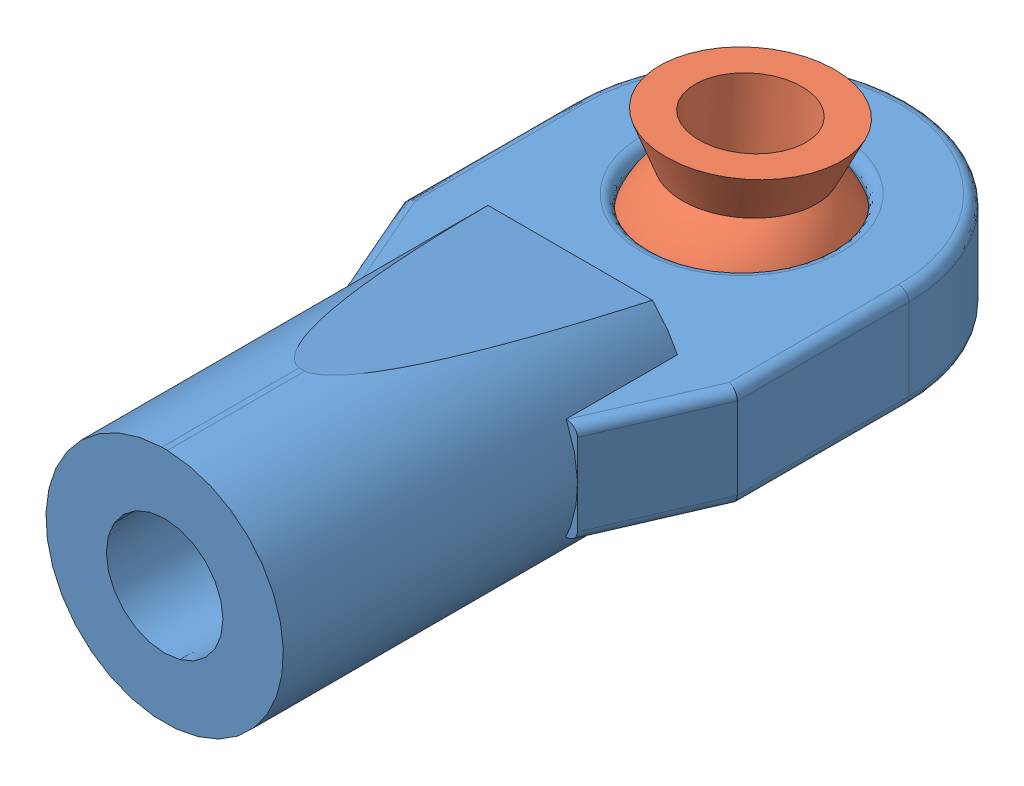
SolidWorks assembly Traxxas_5347, configuration Default. Lengths in mm.
Overall size (9.91 7.38 22.05).
2 component instances, 2 part files, 2 mates.
Components (placement in the parent):
- connector^Traxxas_5347-1: connector^Traxxas_5347 [Default] at (-21.5388 2.7429 3.432) size (9.91 7.03 22.05) (virtual)
- ball^Traxxas_5347-2: ball^Traxxas_5347 [Default] at (-21.5388 2.7429 3.432) x (-0.011157 -0.99789 0.063967) z (-0.255111 0.064694 0.964745) size (6.99 5.78 5.78) (virtual)
Mates (geometry in assembly coordinates):
- Concentric1: concentric: cylinder of connector^Traxxas_5347-1 through (-21.5388 4.2529 3.432) axis (0 -1 0) radius 2.667; sphere of ball^Traxxas_5347-2
- Coincident3: coincident: point of connector^Traxxas_5347-1; point of ball^Traxxas_5347-2
